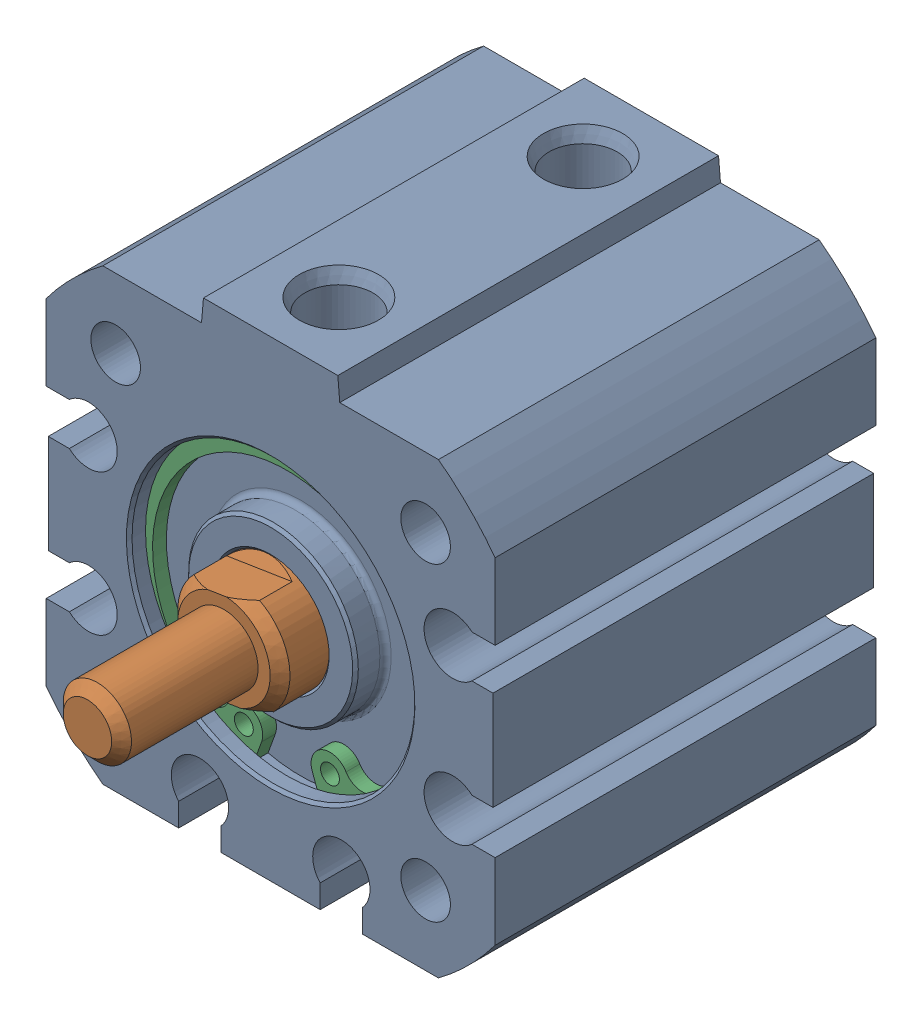
SolidWorks assembly 217-2778-001 Rev2_NCQ8A075-050M, configuration Default. Lengths in mm.
Overall size (31.75 33.34 39.88).
3 component instances, 3 part files, 0 mates.
Components (placement in the parent):
- 217-2778-002_075A-1: 217-2778-002_075A [Default] at origin size (31.75 33.34 26.92)
- 217-2778-003_075M-1: 217-2778-003_075M [Default] at (0 0 -8.85) x (0.156073 -0.987746 0) z (0 0 1) size (18.95 18.95 35.27)
- 217-2778-004_075-1: 217-2778-004_075 [Default] at (0 0 10.362) size (21 20.74 0.97)
